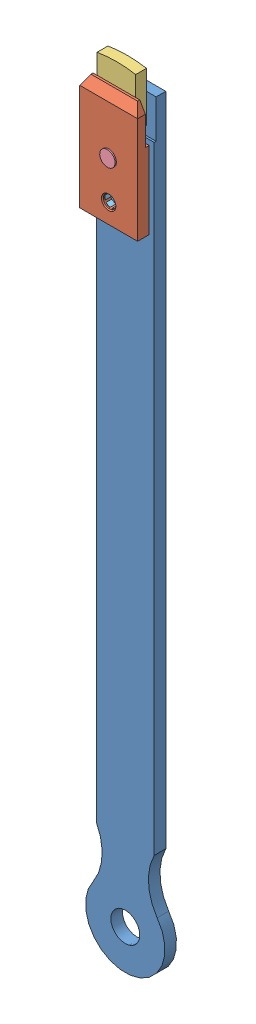
SolidWorks assembly ШаберСб, configuration По умолчанию. Lengths in mm.
Overall size (41.16 411.17 16).
5 component instances, 5 part files, 8 mates.
Components (placement in the parent):
- Ручка8-1: Ручка8 [По умолчанию] at origin size (41.16 400 6)
- Прижим-1: Прижим [По умолчанию] at (0 370 14.6) x (-1 0 0) z (0 0 -1) size (30 60 6)
- Пластина5_6-1: Пластина5_6 [По умолчанию] at (-10 385.328 5) x (1 0 0) z (0 -1 0) size (20 5.6 27.07)
- ВинтМ8_16-3: ВинтМ8_16 [По умолчанию] at (0 370 15.2694) x (1 0 0) z (0 1 0) size (16.96 16 16.96)
- СтопорМ8_8-1: СтопорМ8_8 [По умолчанию] at (0 350 5.45) x (-0.850483 0.526003 0) z (0.526003 0.850483 0) size (8 8 8)
Mates (geometry in assembly coordinates):
- Концентричный3: concentric anti-aligned: cylinder of Ручка8-1 through (0 370 6) axis (0 0 -1) radius 3.25; cylinder of Прижим-1 through (0 370 8.6) axis (0 0 1) radius 3.25
- Расстояние1: distance = 5 mm aligned: plane of Пластина5_6-1 through (10 410.328 10.6) normal (1 0 0); plane of Ручка8-1 through (15 60.1262 6) normal (1 0 0)
- Совпадение7: coincident anti-aligned: plane of Прижим-1 through (15 400 10.6) normal (0 0 -1); plane of Пластина5_6-1 through (2.09 444.0973 10.6) normal (0 0 1)
- Совпадение11: coincident anti-aligned: plane of Ручка8-1 through (20.5785 400 5) normal (0 0 1); plane of Пластина5_6-1 through (2.09 444.0973 5) normal (0 0 -1)
- Концентричный4: concentric anti-aligned: cylinder of Ручка8-1 through (0 350 6) axis (0 0 -1) radius 3.25; cylinder of Прижим-1 through (0 350 8.6) axis (0 0 1) radius 3.25
- Совпадение13: coincident aligned: cone of Ручка8-1 through (0 370 0) axis (0 0 1); cone of ВинтМ8_16-3 through (0 370 4.75) axis (0 0 1)
- Концентричный7: concentric aligned: cylinder of Прижим-1 through (0 350 8.6) axis (0 0 1) radius 3.25; cylinder of СтопорМ8_10-1 through (0 350 74.0946) axis (0 0 1) radius 4
- Совпадение16: coincident aligned: cone of Ручка8-1 through (0 350 5.5) axis (0 0 -1); cone of СтопорМ8_10-1 through (0 350 5.45) axis (0 0 -1)
